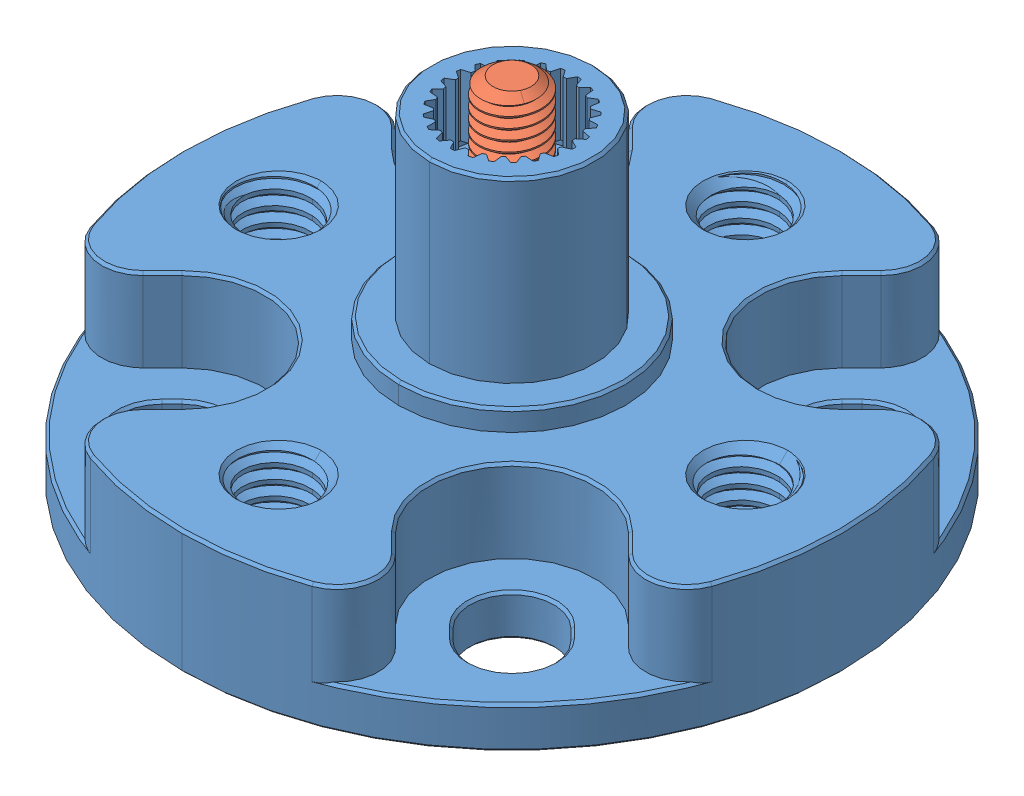
SolidWorks assembly 8 mm shaft 16mm length 1910-0025-0816, configuration Default. Lengths in mm.
Overall size (32 17.1 32).
2 component instances, 2 part files, 0 mates.
Components (placement in the parent):
- 1910-0025-0816.STEP-1: 1910-0025-0816.STEP [Default] at (-26.5689 7.4772 3.7047) size (32 15.6 32)
- 2800-0003-0012.STEP-1: 2800-0003-0012.STEP [Default] at (-26.5689 24.5772 3.7047) x (0.895056 0 0.445953) z (0 1 0) size (5.5 5.5 15.01)
